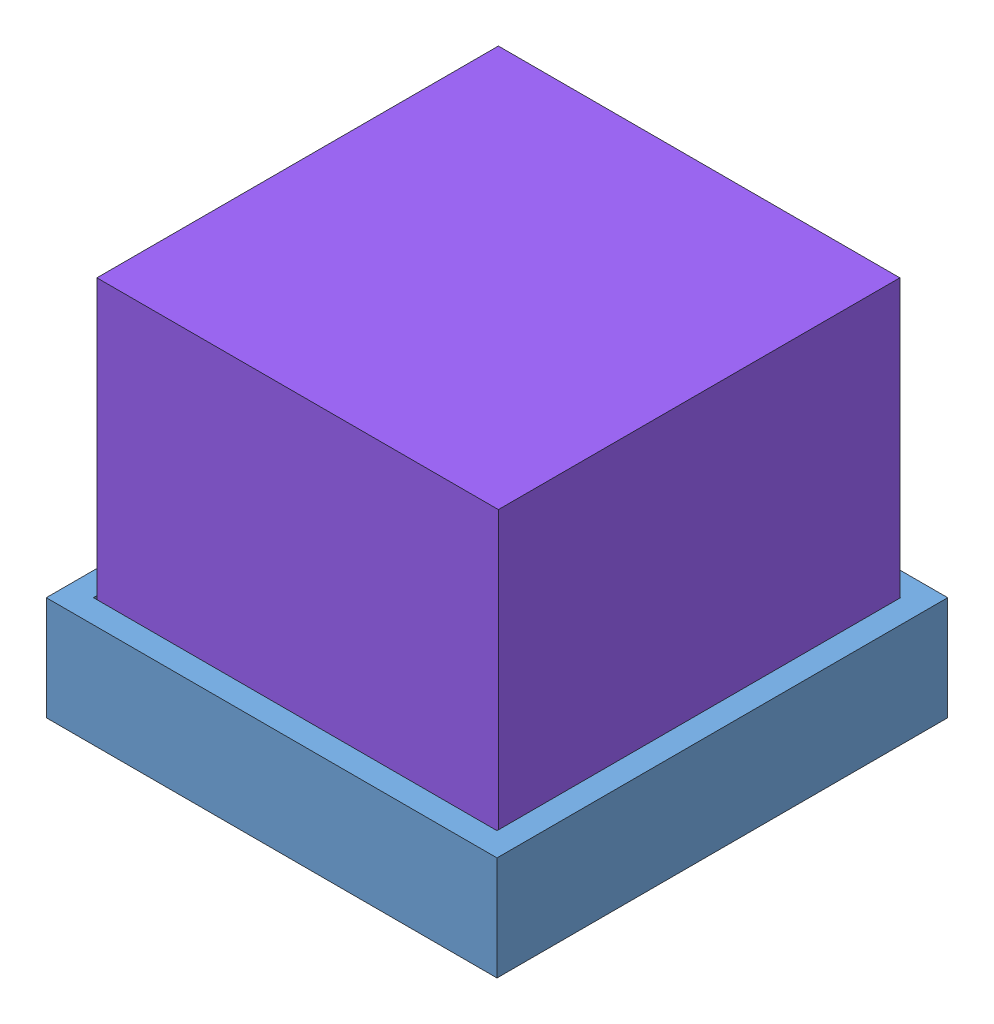
SolidWorks assembly assemble, configuration 默认. Lengths in mm.
Overall size (65 55 65).
47 component instances, 26 part files, 106 mates.
Components (placement in the parent):
- Shell-1: Shell [默认] at (-33.3705 -7.3326 32.5) size (65 15 65)
- screw_M3-10-1: screw_M3-10 [默认] at (-19.3705 -5.3326 46.5) x (0.717304 0 -0.696761) z (0.696761 0 0.717304) size (5.3 13.16 5.3)
- screw_M3-10-2: screw_M3-10 [默认] at (-19.3705 -5.3326 83.5) x (0.397591 0 -0.917563) z (0.917563 0 0.397591) size (5.3 13.16 5.3)
- screw_M3-10-3: screw_M3-10 [默认] at (17.6295 -5.3326 46.5) x (0.995078 0 -0.099092) z (0.099092 0 0.995078) size (5.3 13.16 5.3)
- screw_M3-10-4: screw_M3-10 [默认] at (17.6295 -5.3326 83.5) x (0.739214 0 -0.673471) z (0.673471 0 0.739214) size (5.3 13.16 5.3)
- base-1: base [默认] at (-23.3705 4.6674 42.5) x (0 0 1) z (-1 0 0) size (45 8 45)
- screw_M2-12-1: screw_M2-12 [默认] at (19.8295 10.8674 89.3) x (1 0 0) z (0 1 0) size (3.6 14.58 3.6)
- PZM_BASE_NO_EXTEND-1: PZM_BASE_NO_EXTEND [默认] at (17.1295 12.6674 87.5) size (36 8 20)
- screw_M5_6-1: screw_M5_6 [默认] at (-10.8705 4.6674 77.5) size (8.2 11.14 8.2)
- screw_M5_6-2: screw_M5_6 [默认] at (9.1295 4.6674 77.5) size (8.2 11.14 8.2)
- Scanner_Mount-1: Scanner_Mount [默认] at (-18.8705 36.6674 55) x (0 0 1) z (-1 0 0) size (10 24 36)
- screw_M5_6-3: screw_M5_6 [默认] at (-10.8705 4.6674 60) x (0.99996 0 0.008972) z (-0.008972 0 0.99996) size (8.2 11.14 8.2)
- screw_M5_6-4: screw_M5_6 [默认] at (9.1295 4.6674 60) x (0.999606 0 0.028061) z (-0.028061 0 0.999606) size (8.2 11.14 8.2)
- screw_M2-4-1: screw_M2-4 [默认] at (-0.8705 13.2674 80) x (0.288455 0 -0.957494) z (0.957494 0 0.288455) size (3.6 5.92 3.6)
- screw_M2-4-2: screw_M2-4 [默认] at (-0.8705 13.2674 75) x (0.776269 0 -0.630402) z (0.630402 0 0.776269) size (3.6 5.92 3.6)
- Slider_Bottom-1: Slider_Bottom [默认] at (-3.3705 17.1674 70) size (5 2.75 15)
- Slider_up-1: Slider_up [默认] at (2.6295 21.1674 72.4708) x (-1 0 0) z (0 0 1) size (7 3.85 15)
- pzt-1: pzt [默认] at (-6.7205 19.0174 74.5) x (0 0 -1) z (1 0 0) size (5 2.17 2.05)
- round_megnent-1: round_megnent [默认] at (-5.8705 19.7684 76.5) x (0.672662 -0.73995 0) z (0.73995 0.672662 0) size (3 2 3)
- SAMPLE_TABLE-1: SAMPLE_TABLE [默认] at (4.1295 21.1674 87.4708) x (0 0 -1) z (1 0 0) size (15 4 10)
- sample_PCB-1: sample_PCB [默认] at (-5.8705 25.1674 69.4708) size (10 1.01 17)
- screw_M2-3-1: screw_M2-3 [默认] at (-0.8705 25.2674 82.4708) x (-0.925941 0 -0.377668) z (-0.377668 0 0.925941) size (3.6 4.92 3.6)
- screw_M2-3-2: screw_M2-3 [默认] at (-0.8705 25.2674 77.4708) x (-0.837169 0 -0.546944) z (-0.546944 0 0.837169) size (3.6 4.92 3.6)
- magnent_10x2x5-1: magnent_10x2x5 [默认] at (-5.8705 26.1774 73.4708) x (1 0 0) z (0 1 0) size (10 2 5)
- magnent_10x2x5-2: magnent_10x2x5 [默认] at (-5.8705 26.1774 71.4708) x (1 0 0) z (0 1 0) size (10 2 5)
- screw_M2-4-3: screw_M2-4 [默认] at (2.7295 27.9674 79.4708) x (-0.941608 0 -0.336712) z (-0.336712 0 0.941608) size (3.6 5.92 3.6)
- screw_M2-4-4: screw_M2-4 [默认] at (-4.4705 27.9674 79.4708) x (-0.886769 0 -0.462214) z (-0.462214 0 0.886769) size (3.6 5.92 3.6)
- connector_PCB_component-1: connector_PCB_component [默认] at (17.8915 18.6674 88.836) x (0 0 -1) z (0 1 0) size (15.88 8.89 3.2)
- PiezoCrystal-1: PiezoCrystal [默认] at (-0.8705 27.6674 59) x (0.135622 -0.990761 0) z (0.990761 0.135622 0) size (12 0.23 12)
- pcb_tip_mount-1: pcb_tip_mount [默认] at (3.0498 26.0454 60.6) x (-0.923728 -0.383049 0) z (0 0 -1) size (6 6 8.1)
- tip-1: tip [默认] at (-0.8705 27.6674 63.1) x (-0.796198 -0.605036 0) z (-0.605036 0.796198 0) size (0.3 6 0.3)
- preamp_component-1: preamp_component [默认] at (-13.1115 13.6544 63) size (24.5 8.5 2.4)
- Preamp_cover-1: Preamp_cover [默认] at (-18.8705 23.1674 65) x (0 -1 0) z (-1 0 0) size (10.5 2 36)
- PCB_Connect_component-1: PCB_Connect_component [默认] at (18.3995 11.7754 55) x (-1 0 0) z (0 0 -1) size (36 23.5 3.2)
- Scanner_cover-1: Scanner_cover [默认] at (-0.8705 27.6674 55) x (1 0 0) z (0 1 0) size (22 5 14)
- screw_M3-6-1: screw_M3-6 [默认] at (13.6295 33.6674 50.4) x (0.631433 -0.77543 0) z (-0.77543 -0.631433 0) size (5.3 9.13 5.3)
- screw_M3-6-2: screw_M3-6 [默认] at (13.6295 15.6674 50.4) x (0.631433 -0.77543 0) z (-0.77543 -0.631433 0) size (5.3 9.13 5.3)
- screw_M3-6-5: screw_M3-6 [默认] at (-15.3705 15.6674 50.4) x (0.766967 -0.641687 0) z (-0.641687 -0.766967 0) size (5.3 9.13 5.3)
- screw_M3-6-6: screw_M3-6 [默认] at (-15.3706 33.6674 50.4) x (0.788865 -0.614567 0) z (-0.614567 -0.788865 0) size (5.3 9.13 5.3)
- screw_M3-6-7: screw_M3-6 [默认] at (-8.8705 27.6674 51) x (0.829103 -0.559097 0) z (-0.559097 -0.829103 0) size (5.3 9.13 5.3)
- screw_M3-6-8: screw_M3-6 [默认] at (7.1295 27.6674 51) x (0.857237 -0.514922 0) z (-0.514922 -0.857237 0) size (5.3 9.13 5.3)
- Shell_cover-1: Shell_cover [默认] at (25.2295 47.6674 90.9) x (-1 0 0) z (0 0 1) size (57.9 43 57.9)
- screw_M3-6-9: screw_M3-6 [默认] at (-15.8705 15.6674 70) x (-0.921071 -0.389394 0) z (0.389394 -0.921071 0) size (5.3 9.13 5.3)
- screw_M3-6-10: screw_M3-6 [默认] at (14.1295 15.6674 70) x (-0.891626 -0.452773 0) z (0.452773 -0.891626 0) size (5.3 9.13 5.3)
- screw_M2-4-5: screw_M2-4 [默认] at (14.8795 22.0674 85.5) x (-0.837169 0 -0.546944) z (-0.546944 0 0.837169) size (3.6 5.92 3.6)
- screw_M2-4-6: screw_M2-4 [默认] at (14.8795 22.0674 73.5) x (-0.731557 0 -0.68178) z (-0.68178 0 0.731557) size (3.6 5.92 3.6)
- screw_M2-4-7: screw_M2-4 [默认] at (9.3795 22.0674 85.5) x (-0.999731 0 0.023176) z (0.023176 0 0.999731) size (3.6 5.92 3.6)
Mates (geometry in assembly coordinates):
- 同心1: concentric anti-aligned: circle of Shell-1; circle of screw_M3-15-1
- 同心2: concentric anti-aligned: circle of Shell-1; circle of screw_M3-15-2
- 同心3: concentric anti-aligned: circle of Shell-1; circle of screw_M3-15-3
- 同心4: concentric anti-aligned: circle of Shell-1; circle of screw_M3-15-4
- 同心6: concentric aligned: circle of Shell-1; circle of base-1
- 同心7: concentric aligned: circle of Shell-1; circle of base-1
- 重合2: coincident anti-aligned: circle of base-1; circle of screw_M2-12-1
- 同心8: concentric anti-aligned: circle of base-1; circle of PZM_BASE_NO_EXTEND-1
- 同心9: concentric anti-aligned: circle of base-1; circle of PZM_BASE_NO_EXTEND-1
- 同心10: concentric anti-aligned: circle of base-1; circle of screw_M5_6-1
- 同心11: concentric anti-aligned: circle of base-1; circle of screw_M5_6-2
- 重合3: coincident anti-aligned: plane of Shell-1 through (-19.3705 -2.3326 83.5) normal (0 -1 0); plane of screw_M3-10-2 through (-19.3705 -2.3326 83.5) normal (0 1 0)
- 重合4: coincident anti-aligned: plane of Shell-1 through (-19.3705 -2.3326 46.5) normal (0 -1 0); plane of screw_M3-10-1 through (-19.3705 -2.3326 46.5) normal (0 1 0)
- 重合5: coincident anti-aligned: plane of Shell-1 through (17.6295 -2.3326 46.5) normal (0 -1 0); plane of screw_M3-10-3 through (17.6295 -2.3326 46.5) normal (0 1 0)
- 重合6: coincident anti-aligned: plane of Shell-1 through (17.6295 -2.3326 83.5) normal (0 -1 0); plane of screw_M3-10-4 through (17.6295 -2.3326 83.5) normal (0 1 0)
- 同心12: concentric anti-aligned: circle of base-1; circle of Scanner_Mount-1
- 同心13: concentric anti-aligned: circle of base-1; circle of Scanner_Mount-1
- 同心14: concentric anti-aligned: circle of base-1; circle of screw_M5_6-3
- 同心15: concentric anti-aligned: circle of base-1; circle of screw_M5_6-4
- 重合7: coincident anti-aligned: plane of base-1 through (9.1295 9.6674 60) normal (0 -1 0); plane of screw_M5_6-4 through (9.1295 9.6674 60) normal (0 1 0)
- 重合8: coincident anti-aligned: plane of base-1 through (-10.8705 9.6674 60) normal (0 -1 0); plane of screw_M5_6-3 through (-10.8705 9.6674 60) normal (0 1 0)
- 重合9: coincident anti-aligned: plane of base-1 through (-10.8705 9.6674 77.5) normal (0 -1 0); plane of screw_M5_6-1 through (-10.8705 9.6674 77.5) normal (0 1 0)
- 重合10: coincident anti-aligned: plane of base-1 through (9.1295 9.6674 77.5) normal (0 -1 0); plane of screw_M5_6-2 through (9.1295 9.6674 77.5) normal (0 1 0)
- 重合11: coincident anti-aligned: plane of Shell-1 through (-33.3705 4.6674 32.5) normal (0 1 0); plane of base-1 through (-23.3705 4.6674 42.5) normal (0 -1 0)
- 同心16: concentric aligned: circle of PZM_BASE_NO_EXTEND-1; circle of screw_M2-6-1
- 同心17: concentric anti-aligned: circle of PZM_BASE_NO_EXTEND-1; circle of screw_M2-6-2
- 重合12: coincident anti-aligned: plane of PZM_BASE_NO_EXTEND-1 through (-0.8705 15.0674 80) normal (0 -1 0); plane of screw_M2-4-1 through (-0.8705 15.0674 80) normal (0 1 0)
- 重合13: coincident anti-aligned: plane of PZM_BASE_NO_EXTEND-1 through (-0.8705 15.0674 75) normal (0 -1 0); plane of screw_M2-4-2 through (-0.8705 15.0674 75) normal (0 1 0)
- 同心18: concentric anti-aligned: circle of PZM_BASE_NO_EXTEND-1; circle of Slider_Bottom-1
- 同心19: concentric anti-aligned: circle of PZM_BASE_NO_EXTEND-1; circle of Slider_Bottom-1
- 重合14: coincident anti-aligned: plane of PZM_BASE_NO_EXTEND-1 through (17.1295 17.1674 87.5) normal (0 1 0); plane of Slider_Bottom-1 through (-3.3705 17.1674 70) normal (0 -1 0)
- 重合17: coincident anti-aligned: line of Slider_Bottom-1 through (-3.3705 19.9174 70) axis (0 0 1); line of Slider_up-1 through (-3.3705 19.9174 87.4708) axis (0 0 -1)
- 重合18: coincident aligned: line of Slider_Bottom-1 through (1.6295 19.9174 85) axis (0 0 -1); line of Slider_up-1 through (1.6295 19.9174 87.4708) axis (0 0 -1)
- 重合20: coincident anti-aligned: plane of PZM_BASE_NO_EXTEND-1 through (-4.8705 17.1674 69.5) normal (0 0 1); plane of pzt-1 through (-6.7205 20.6674 69.5) normal (0 0 -1)
- 重合21: coincident aligned: plane of PZM_BASE_NO_EXTEND-1 through (17.1295 20.6674 87.5) normal (0 1 0); plane of pzt-1 through (-6.7205 20.6674 74.5) normal (0 1 0)
- 重合22: coincident aligned: plane of PZM_BASE_NO_EXTEND-1 through (-4.8705 17.1674 67.5) normal (1 0 0); plane of pzt-1 through (-4.8705 19.0174 74.5) normal (1 0 0)
- 重合23: coincident anti-aligned: plane of pzt-1 through (-6.7205 20.6674 74.5) normal (0 0 1); plane of round_megnent-1 through (-5.8705 19.7684 74.5) normal (0 0 -1)
- 相切1: tangent anti-aligned: plane of Slider_up-1 through (-4.3705 20.1674 72.4708) normal (-1 0 0); cylinder of round_megnent-1 through (-5.8705 19.7684 74.5) axis (0 0 1) radius 1.5
- 锁定1: lock: unknown of PZM_BASE_NO_EXTEND-1; unknown of round_megnent-1
- 同心22: concentric anti-aligned: circle of Slider_up-1; circle of SAMPLE_TABLE-1
- 同心23: concentric aligned: circle of Slider_up-1; circle of SAMPLE_TABLE-1
- 重合24: coincident anti-aligned: plane of Slider_up-1 through (2.6295 21.1674 72.4708) normal (0 1 0); plane of SAMPLE_TABLE-1 through (4.1295 21.1674 87.4708) normal (0 -1 0)
- 重合25: coincident anti-aligned: plane of base-1 through (-23.3705 12.6674 42.5) normal (0 1 0); plane of PZM_BASE_NO_EXTEND-1 through (17.1295 12.6674 87.5) normal (0 -1 0)
- 同心24: concentric aligned: circle of SAMPLE_TABLE-1; circle of sample_PCB-1
- 同心25: concentric aligned: circle of SAMPLE_TABLE-1; circle of sample_PCB-1
- 同心26: concentric aligned: circle of SAMPLE_TABLE-1; circle of screw_M2-3-2
- 同心27: concentric aligned: circle of SAMPLE_TABLE-1; circle of screw_M2-3-1
- 重合27: coincident anti-aligned: plane of SAMPLE_TABLE-1 through (-0.8705 23.4674 77.4708) normal (0 1 0); plane of screw_M2-3-2 through (-0.8705 23.4674 77.4708) normal (0 -1 0)
- 重合28: coincident anti-aligned: plane of SAMPLE_TABLE-1 through (-0.8705 23.4674 82.4708) normal (0 1 0); plane of screw_M2-3-1 through (-0.8705 23.4674 82.4708) normal (0 -1 0)
- 重合29: coincident anti-aligned: plane of SAMPLE_TABLE-1 through (4.1295 25.1674 87.4708) normal (0 1 0); plane of sample_PCB-1 through (-5.8705 25.1674 69.4708) normal (0 -1 0)
- 重合31: coincident anti-aligned: plane of sample_PCB-1 through (-5.8705 26.1774 69.4708) normal (0 1 0); plane of magnent_10x2x5-1 through (-5.8705 26.1774 71.4708) normal (0 -1 0)
- 重合32: coincident aligned: plane of sample_PCB-1 through (-5.8705 26.1674 69.4708) normal (-1 0 0); plane of magnent_10x2x5-1 through (-5.8705 26.1774 71.4708) normal (-1 0 0)
- 重合33: coincident anti-aligned: plane of sample_PCB-1 through (-5.8705 26.1774 69.4708) normal (0 1 0); plane of magnent_10x2x5-2 through (-5.8705 26.1774 69.4708) normal (0 -1 0)
- 重合34: coincident aligned: plane of sample_PCB-1 through (-5.8705 26.1674 69.4708) normal (-1 0 0); plane of magnent_10x2x5-2 through (-5.8705 26.1774 69.4708) normal (-1 0 0)
- 重合35: coincident anti-aligned: plane of magnent_10x2x5-1 through (-5.8705 26.1774 71.4708) normal (0 0 -1); plane of magnent_10x2x5-2 through (-5.8705 26.1774 71.4708) normal (0 0 1)
- 重合36: coincident aligned: plane of sample_PCB-1 through (-5.8705 26.1674 69.4708) normal (0 0 -1); plane of magnent_10x2x5-2 through (-5.8705 26.1774 69.4708) normal (0 0 -1)
- 同心28: concentric anti-aligned: circle of sample_PCB-1; circle of screw_M2-4-4
- 同心29: concentric anti-aligned: circle of sample_PCB-1; circle of screw_M2-4-3
- 重合37: coincident anti-aligned: plane of sample_PCB-1 through (-5.8705 26.1674 69.4708) normal (0 1 0); plane of screw_M2-4-3 through (2.7295 26.1674 79.4708) normal (0 -1 0)
- 重合38: coincident anti-aligned: plane of sample_PCB-1 through (-5.8705 26.1674 69.4708) normal (0 1 0); plane of screw_M2-4-4 through (-4.4705 26.1674 79.4708) normal (0 -1 0)
- 重合39: coincident anti-aligned: plane of PZM_BASE_NO_EXTEND-1 through (17.1295 18.6674 87.5) normal (0 1 0); plane of connector_PCB_component-1 through (17.8915 18.6674 88.836) normal (0 -1 0)
- 同心31: concentric aligned: circle of PZM_BASE_NO_EXTEND-1; circle of connector_PCB_component-1
- 同心32: concentric aligned: circle of PZM_BASE_NO_EXTEND-1; circle of connector_PCB_component-1
- 同心34: concentric aligned: circle of Scanner_Mount-1; circle of PiezoCrystal-1
- 重合40: coincident anti-aligned: plane of Scanner_Mount-1 through (-0.8705 27.6674 59) normal (0 0 -1); plane of PiezoCrystal-1 through (-0.8705 27.6674 59) normal (0 0 1)
- 同心35: concentric aligned: circle of Scanner_Mount-1; circle of pcb_tip_mount-1
- 重合41: coincident anti-aligned: plane of PiezoCrystal-1 through (-0.8705 27.6674 59) normal (0 0 1); plane of pcb_tip_mount-1 through (-0.8705 27.6674 59) normal (0 0 -1)
- 同心36: concentric aligned: circle of pcb_tip_mount-1; circle of tip-1
- 重合42: coincident anti-aligned: plane of pcb_tip_mount-1 through (-0.8705 27.6674 63.1) normal (0 0 1); plane of tip-1 through (-0.8705 27.6674 63.1) normal (0 0 -1)
- 重合43: coincident anti-aligned: plane of Scanner_Mount-1 through (-18.8705 36.6674 63) normal (0 0 1); plane of preamp_component-1 through (-13.1115 13.6544 63) normal (0 0 -1)
- 同心37: concentric aligned: circle of Scanner_Mount-1; circle of preamp_component-1
- 重合44: coincident anti-aligned: plane of Scanner_Mount-1 through (-18.8705 36.6674 65) normal (0 0 1); plane of Preamp_cover-1 through (-18.8705 23.1674 65) normal (0 0 -1)
- 同心38: concentric anti-aligned: circle of Scanner_Mount-1; circle of Preamp_cover-1
- 同心39: concentric anti-aligned: circle of Scanner_Mount-1; circle of Preamp_cover-1
- 重合45: coincident anti-aligned: plane of base-1 through (-23.3705 12.6674 42.5) normal (0 1 0); plane of Scanner_Mount-1 through (-18.8705 12.6674 65) normal (0 -1 0)
- 重合46: coincident anti-aligned: plane of Scanner_Mount-1 through (-18.8705 36.6674 55) normal (0 0 -1); plane of PCB_Connect_component-1 through (18.3995 11.7754 55) normal (0 0 1)
- 同心40: concentric aligned: circle of Scanner_Mount-1; circle of PCB_Connect_component-1
- 同心41: concentric aligned: circle of Scanner_Mount-1; circle of PCB_Connect_component-1
- 同心42: concentric aligned: circle of Scanner_Mount-1; circle of Scanner_cover-1
- 同心43: concentric aligned: circle of Scanner_cover-1; circle of Scanner_Mount-1
- 重合47: coincident anti-aligned: plane of Scanner_Mount-1 through (-18.8705 36.6674 55) normal (0 0 -1); plane of Scanner_cover-1 through (-0.8705 27.6674 55) normal (0 0 1)
- 同心45: concentric anti-aligned: circle of PCB_Connect_component-1; circle of screw_M3-6-1
- 重合48: coincident anti-aligned: plane of PCB_Connect_component-1 through (18.3995 11.7754 53.4) normal (0 0 -1); plane of screw_M3-6-1 through (13.6295 33.6674 53.4) normal (0 0 1)
- 同心46: concentric anti-aligned: circle of PCB_Connect_component-1; circle of screw_M3-6-2
- 同心47: concentric anti-aligned: circle of PCB_Connect_component-1; circle of screw_M3-6-5
- 同心48: concentric anti-aligned: circle of PCB_Connect_component-1; circle of screw_M3-6-6
- 同心49: concentric anti-aligned: circle of Scanner_cover-1; circle of screw_M3-6-8
- 同心50: concentric anti-aligned: circle of Scanner_cover-1; circle of screw_M3-6-7
- 重合49: coincident anti-aligned: plane of PCB_Connect_component-1 through (18.3995 11.7754 53.4) normal (0 0 -1); plane of screw_M3-6-2 through (13.6295 15.6674 53.4) normal (0 0 1)
- 重合50: coincident anti-aligned: plane of PCB_Connect_component-1 through (18.3995 11.7754 53.4) normal (0 0 -1); plane of screw_M3-6-6 through (-15.3706 33.6674 53.4) normal (0 0 1)
- 重合51: coincident anti-aligned: plane of PCB_Connect_component-1 through (18.3995 11.7754 53.4) normal (0 0 -1); plane of screw_M3-6-5 through (-15.3705 15.6674 53.4) normal (0 0 1)
- 重合52: coincident anti-aligned: plane of Scanner_cover-1 through (-0.8705 27.6674 54) normal (0 0 -1); plane of screw_M3-6-7 through (-8.8705 27.6674 54) normal (0 0 1)
- 重合53: coincident anti-aligned: plane of Scanner_cover-1 through (-0.8705 27.6674 54) normal (0 0 -1); plane of screw_M3-6-8 through (7.1295 27.6674 54) normal (0 0 1)
- 重合54: coincident: plane of Shell-1 through (-33.3705 4.6674 32.5) normal (0 1 0); plane of Shell_cover-1 through (25.2295 4.6674 90.9) normal (0 -1 0)
- 距离1: distance = 0.1 mm: plane of Shell_cover-1 through (28.2295 44.6674 36) normal (0 0 -1); plane of Shell-1 through (28.2295 4.6674 35.9) normal (0 0 1)
- 重合56: coincident anti-aligned: plane of Shell-1 through (28.2295 4.6674 35.9) normal (-1 0 0); plane of Shell_cover-1 through (28.2295 44.6674 93.9) normal (1 0 0)
- 同心51: concentric: circle of Preamp_cover-1; circle of screw_M3-6-9
- 重合57: coincident anti-aligned: plane of Preamp_cover-1 through (-18.8705 23.1674 67) normal (0 0 1); plane of screw_M3-6-9 through (-15.8705 15.6674 67) normal (0 0 -1)
- 同心52: concentric: circle of Preamp_cover-1; circle of screw_M3-6-10
- 重合58: coincident anti-aligned: plane of Preamp_cover-1 through (-18.8705 23.1674 67) normal (0 0 1); plane of screw_M3-6-10 through (14.1295 15.6674 67) normal (0 0 -1)
- 同心53: concentric: circle of connector_PCB_component-1; circle of screw_M2-4-5
- 重合59: coincident anti-aligned: plane of connector_PCB_component-1 through (17.8915 20.2674 88.836) normal (0 1 0); plane of screw_M2-4-5 through (14.8795 20.2674 85.5) normal (0 -1 0)
- 同心54: concentric: circle of connector_PCB_component-1; circle of screw_M2-4-7
- 重合60: coincident anti-aligned: plane of connector_PCB_component-1 through (17.8915 20.2674 88.836) normal (0 1 0); plane of screw_M2-4-7 through (9.3795 20.2674 85.5) normal (0 -1 0)
- 同心55: concentric: circle of connector_PCB_component-1; circle of screw_M2-4-6
- 重合61: coincident anti-aligned: plane of connector_PCB_component-1 through (17.8915 20.2674 88.836) normal (0 1 0); plane of screw_M2-4-6 through (14.8795 20.2674 73.5) normal (0 -1 0)
